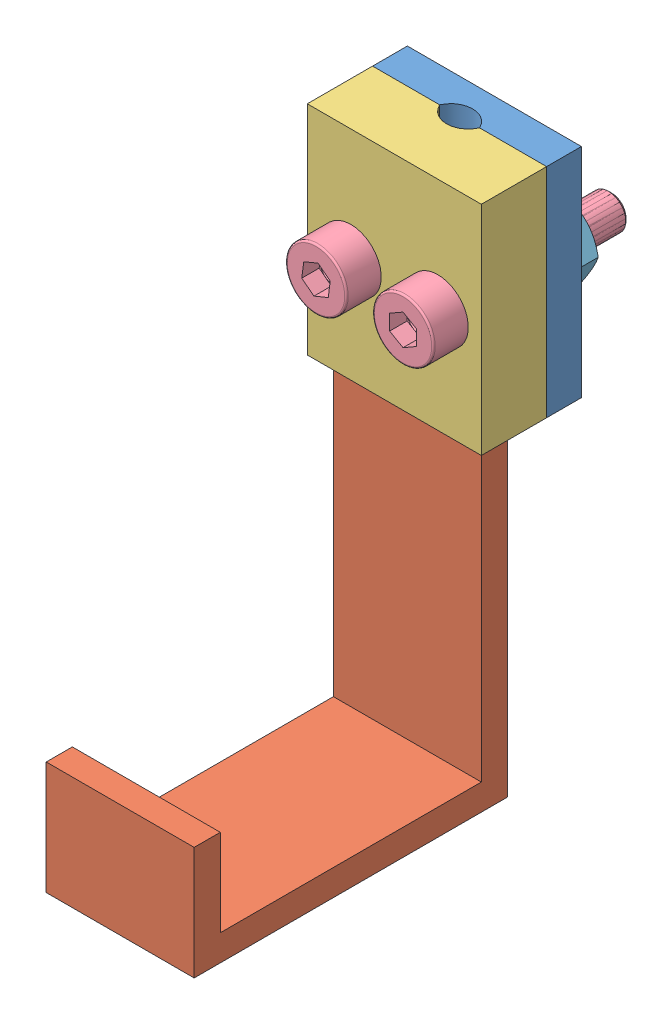
SolidWorks assembly Systeme fixation crochet + cable 25mm, configuration Défaut. Lengths in mm.
Overall size (20.16 62 51.5).
7 component instances, 5 part files, 14 mates.
Components (placement in the parent):
- Systeme fixation cable 20x25-1: Systeme fixation cable 20x25 [Défaut] at (-26.4252 -18.5869 -2) size (20 25 4)
- Crochet vélo carré 30mm-1: Crochet vélo carré 30mm [Défaut] at (-24.9252 4.4131 8) x (0 0 -1) z (1 0 0) size (36 60 17)
- Systeme fixation crochet 20x25-1: Systeme fixation crochet 20x25 [Défaut] at (-26.4252 6.4131 9.5) x (1 0 0) z (0 0 -1) size (20 25 7.5)
- socket head cap screw_iso-2: socket head cap screw_iso [ISO 4762 M4 x 20 - 20C] at (-21.4252 -6.5869 13.5) x (0 0 -1) z (-0.381849 0.924225 0) size (24 7 7)
- socket head cap screw_iso-3: socket head cap screw_iso [ISO 4762 M4 x 20 - 20C] at (-11.4252 -6.5869 13.5) x (0 0 -1) z (-1 0 0) size (24 7 7)
- hex nut style 1 gradeab_iso-1: hex nut style 1 gradeab_iso [ISO - 4032 - M4 - W - C] at (-21.4252 -6.5869 -5.2) x (0.856705 0.515806 0) z (0 0 -1) size (7 8.08 3.2)
- hex nut style 1 gradeab_iso-2: hex nut style 1 gradeab_iso [ISO - 4032 - M4 - W - C] at (-11.4252 -6.5869 -5.2) x (-0.859678 -0.510835 0) z (0 0 -1) size (7 8.08 3.2)
Mates (geometry in assembly coordinates):
- Coïncidente1: coincident anti-aligned: plane of Systeme fixation cable 20x25-1 through (-26.4252 -18.5869 2) normal (0 0 1); plane of Systeme fixation crochet 20x25-1 through (-26.4252 6.4131 2) normal (0 0 -1)
- Coïncidente2: coincident aligned: plane of Systeme fixation cable 20x25-1 through (-26.4252 6.4131 2) normal (0 1 0); plane of Systeme fixation crochet 20x25-1 through (-26.4252 6.4131 2) normal (0 1 0)
- Coaxiale1: concentric anti-aligned: cylinder of Systeme fixation cable 20x25-1 through (-11.4252 -6.5869 2) axis (0 0 -1) radius 2; cylinder of Systeme fixation crochet 20x25-1 through (-11.4252 -6.5869 2) axis (0 0 1) radius 2
- Coïncidente3: coincident anti-aligned: plane of Crochet vélo carré 30mm-1 through (-7.9252 4.4131 8) normal (0 0 1); plane of Systeme fixation crochet 20x25-1 through (-24.9252 4.4131 8) normal (0 0 -1)
- Coïncidente4: coincident anti-aligned: plane of Crochet vélo carré 30mm-1 through (-7.9252 4.4131 8) normal (1 0 0); plane of Systeme fixation crochet 20x25-1 through (-7.9252 4.4131 8) normal (-1 0 0)
- Coïncidente5: coincident anti-aligned: plane of Crochet vélo carré 30mm-1 through (-7.9252 4.4131 8) normal (0 1 0); plane of Systeme fixation crochet 20x25-1 through (-26.4252 4.4131 9.5) normal (0 -1 0)
- Coaxiale5: concentric aligned: cylinder of Systeme fixation crochet 20x25-1 through (-21.4252 -6.5869 2) axis (0 0 1) radius 2; cylinder of socket head cap screw_iso-2 through (-21.4252 -6.5869 45.25) axis (0 0 1) radius 3.5
- Coïncidente8: coincident anti-aligned: plane of Systeme fixation crochet 20x25-1 through (-26.4252 6.4131 9.5) normal (0 0 1); plane of socket head cap screw_iso-2 through (-24.66 -7.9234 9.5) normal (0 0 -1)
- Coaxiale6: concentric aligned: cylinder of Systeme fixation crochet 20x25-1 through (-11.4252 -6.5869 2) axis (0 0 1) radius 2; cylinder of socket head cap screw_iso-3 through (-11.4252 -6.5869 45.25) axis (0 0 1) radius 3.5
- Coïncidente9: coincident anti-aligned: plane of Systeme fixation crochet 20x25-1 through (-26.4252 6.4131 9.5) normal (0 0 1); plane of socket head cap screw_iso-3 through (-11.4252 -10.0869 9.5) normal (0 0 -1)
- Coaxiale9: concentric aligned: cylinder of Systeme fixation cable 20x25-1 through (-21.4252 -6.5869 2) axis (0 0 -1) radius 2; cylinder of hex nut style 1 gradeab_iso-1 through (-21.4252 -6.5869 19.8375) axis (0 0 -1) radius 2
- Coïncidente11: coincident anti-aligned: plane of Systeme fixation cable 20x25-1 through (-26.4252 -18.5869 -2) normal (0 0 -1); plane of hex nut style 1 gradeab_iso-1 through (-19.3406 -10.0493 -2) normal (0 0 1)
- Coaxiale10: concentric aligned: cylinder of Systeme fixation cable 20x25-1 through (-11.4252 -6.5869 2) axis (0 0 -1) radius 2; cylinder of hex nut style 1 gradeab_iso-2 through (-11.4252 -6.5869 19.8375) axis (0 0 -1) radius 2
- Coïncidente12: coincident anti-aligned: plane of Systeme fixation cable 20x25-1 through (-26.4252 -18.5869 -2) normal (0 0 -1); plane of hex nut style 1 gradeab_iso-2 through (-13.4897 -3.1126 -2) normal (0 0 1)
